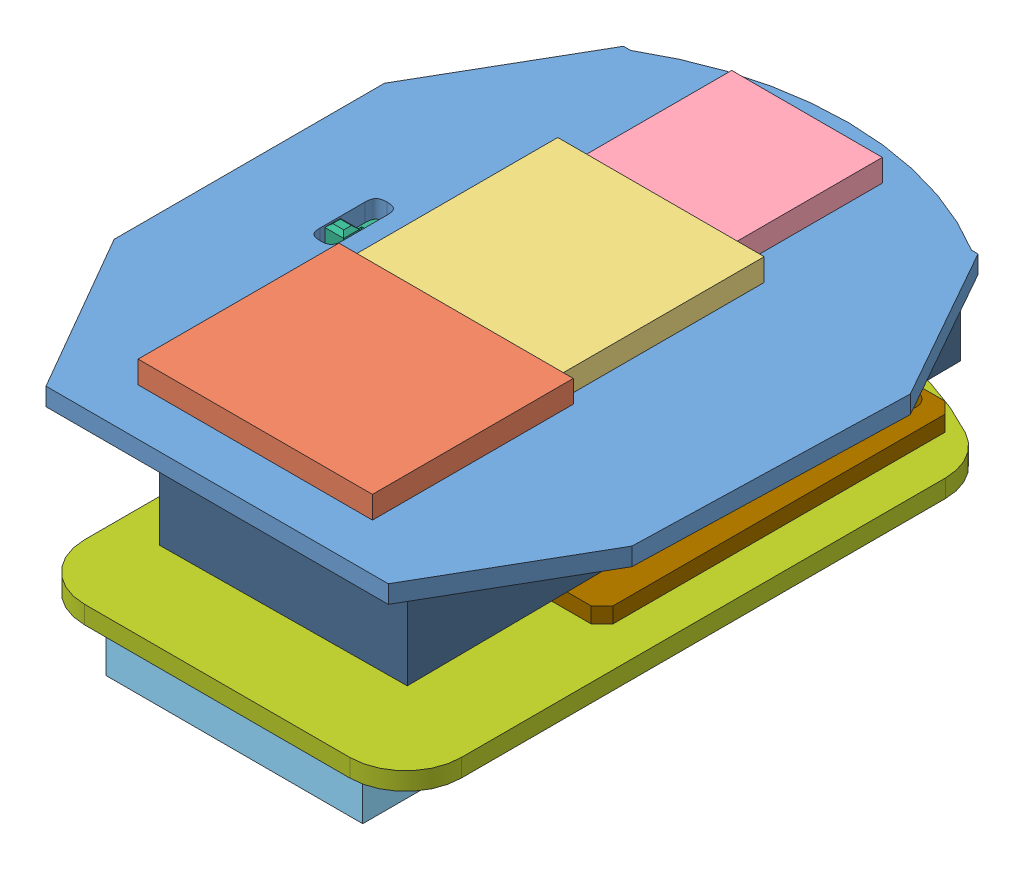
SolidWorks assembly perf_payload, configuration Default. Lengths in mm.
Overall size (47.68 22.8 56.41).
10 component instances, 10 part files, 15 mates.
Components (placement in the parent):
- perfboard_pl-1: perfboard_pl [Default] at origin size (47.68 1.7 56.41)
- CCS811-1: CCS811 [Default] at (-63.7913 1.6 50.697) size (21 2 18)
- ISL29125-1: ISL29125 [Default] at (-81.9294 1.6 26.7737) size (18.5 2 18)
- VEML6070-1: VEML6070 [Default] at (-58.9407 1.6 11.4703) size (13.5 2 13)
- featherM0LORA-1: featherM0LORA [Default] at (-99.6799 -17.2 -2.9628) size (23 4 51)
- SMD Switch-1: SMD Switch [Default] at (-114.5109 -3.1 22.6076) x (0 0 -1) z (1 0 0) size (8.7 9.4 3.86)
- perfboard_pl_2-1: perfboard_pl_2 [Default] at (0 -15.2 0) size (33.78 1.6 56.41)
- perfboard_pl_3-1: perfboard_pl_3 [Default] at (-14.0679 -9.6 -10.7999) size (8.64 1.6 33.02)
- Micro SD-1: Micro SD [Default] at (-101.2748 -13.6 13.7688) x (0 0 1) z (0 1 0) size (31.75 25.4 3.4)
- Lipo750A-1: Lipo750A [Default] at (-91.5331 -3.0405 -3.4133) x (0.999963 0 -0.008628) z (0.008628 0 0.999963) size (22 8 50)
Mates (geometry in assembly coordinates):
- Coincident1: coincident anti-aligned: plane of perfboard_pl-1 through (-100.1969 1.6 22.5043) normal (0 1 0); plane of ISL29125-1 through (-81.9294 1.6 26.7737) normal (0 -1 0)
- Coincident2: coincident anti-aligned: plane of perfboard_pl-1 through (-100.1969 1.6 22.5043) normal (0 1 0); plane of CCS811-1 through (-63.7913 1.6 50.697) normal (0 -1 0)
- Coincident3: coincident anti-aligned: plane of perfboard_pl-1 through (-100.1969 1.6 22.5043) normal (0 1 0); plane of VEML6070-1 through (-58.9407 1.6 11.4703) normal (0 -1 0)
- Coincident9: coincident aligned: plane of perfboard_pl-1 through (-115.5329 1.6 49.0671) normal (0 0 1); plane of perfboard_pl_2-1 through (-117.0879 -15 49.0671) normal (0 0 1)
- Distance1: distance = 13.6 mm anti-aligned: plane of perfboard_pl-1 through (-100.1969 0 22.5043) normal (0 -1 0); plane of perfboard_pl_2-1 through (-100.1969 -13.6 22.5043) normal (0 1 0)
- Coincident11: coincident anti-aligned: plane of CCS811-1 through (-90.5061 3.6 26.8396) normal (0 0 -1); plane of ISL29125-1 through (-91.4001 3.6 26.8396) normal (0 0 1)
- Coincident12: coincident anti-aligned: plane of ISL29125-1 through (-109.9001 3.6 8.8396) normal (0 0 -1); plane of VEML6070-1 through (-107.3136 3.6 8.8396) normal (0 0 1)
- Concentric1: concentric aligned: cylinder of perfboard_pl-1 through (-100.1969 1.6 22.5043) axis (0 -1 0) radius 29.85; cylinder of perfboard_pl_2-1 through (-100.1969 -15 22.5043) axis (0 -1 0) radius 29.85
- Coincident13: coincident anti-aligned: plane of featherM0LORA-1 through (-111.1799 -16.6 48.0372) normal (0 1 0); plane of perfboard_pl_2-1 through (-100.1969 -16.6 22.5043) normal (0 -1 0)
- Coincident14: coincident anti-aligned: plane of perfboard_pl-1 through (-100.1969 0 22.5043) normal (0 -1 0); plane of SMD Switch-1 through (-114.5109 0 22.6076) normal (0 1 0)
- Parallel1: parallel anti-aligned: plane of perfboard_pl-1 through (-115.5329 1.6 49.0671) normal (0 0 1); plane of SMD Switch-1 through (-116.4109 0 18.2576) normal (0 0 -1)
- Distance2: distance = 4 mm anti-aligned: plane of SMD Switch-1 through (-114.5109 -4 22.6076) normal (0 -1 0); plane of perfboard_pl_3-1 through (-14.0679 -8 -10.7999) normal (0 1 0)
- Coincident16: coincident anti-aligned: plane of perfboard_pl_2-1 through (-100.1969 -15 22.5043) normal (0 1 0); plane of Micro SD-1 through (-101.2748 -15 13.7688) normal (0 -1 0)
- Parallel2: parallel aligned: plane of perfboard_pl_2-1 through (-117.0879 -15 49.0671) normal (0 0 1); plane of Micro SD-1 through (-111.2748 -13.6 27.8953) normal (0 0 1)
- Coincident17: coincident anti-aligned: plane of perfboard_pl-1 through (-100.1969 0 22.5043) normal (0 -1 0); plane of Lipo750A-1 through (-85.6849 0 46.5381) normal (0 1 0)
